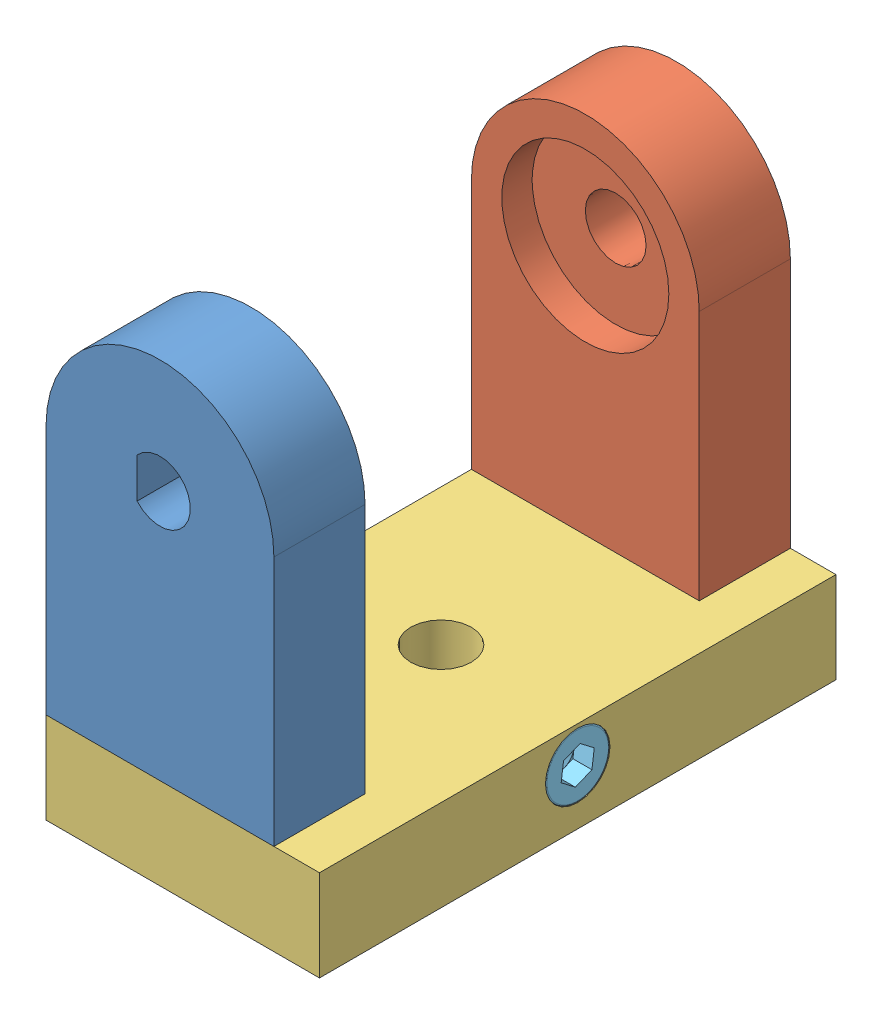
SolidWorks assembly Link2, configuration Default. Lengths in mm.
Overall size (36 60 68.86).
9 component instances, 5 part files, 1 mates.
Components (placement in the parent):
- ConnectingJoint-1: ConnectingJoint [Default] at (-13.0484 0 -9.0061) size (36 60 68.86)
  - BearingJoints-1: BearingJoints [Default] at (10.0484 39.9223 31.0061) size (30 48 12)
  - BearingJoints2-1: BearingJoints2 [Default] at (10.0484 39.9223 -12.9939) x (-1 0 0) z (0 0 -1) size (30 48 12)
  - JointBottom-1: JointBottom [Default] at (13.0484 -5.0777 9.0061) x (0 0 -1) z (1 0 0) size (68 12 36)
  - socket head cap screw_iso-1: socket head cap screw_iso [ISO 4762 M6 x 20 - 20S] at (3.0484 -5.0777 -18.9939) x (0 1 0) z (-0.488199 0 0.872732) size (26 10 10)
  - socket head cap screw_iso-2: socket head cap screw_iso [ISO 4762 M6 x 20 - 20S] at (3.0484 -5.0777 37.0061) x (0 1 0) z (0 0 1) size (26 10 10)
  - socket head cap screw_iso-3: socket head cap screw_iso [ISO 4762 M6 x 20 - 20S] at (17.0484 -5.0777 37.0061) x (0 1 0) z (0 0 1) size (26 10 10)
  - socket head cap screw_iso-4: socket head cap screw_iso [ISO 4762 M6 x 20 - 20S] at (17.0484 -5.0777 -18.9939) x (0 1 0) z (-0.513591 0 0.858035) size (26 10 10)
  - M5X10-1: M5X10 [Default] at (22.2578 2.0842 9.2195) x (-1 0 0) z (0 -0.924225 -0.381849) size (15 8.5 8.5)
Mates (geometry in assembly coordinates):
- Concentric1: concentric: cylinder of ConnectingJoint-1/JointBottom-1 through (0 -1.0777 0) axis (0 -1 0) radius 11
